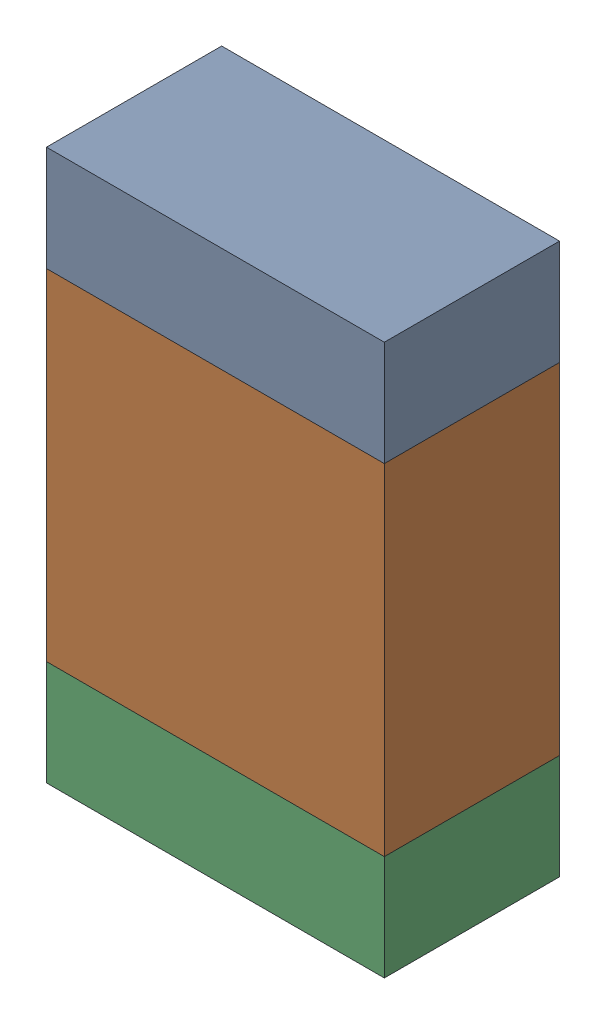
SolidWorks assembly R9-2, configuration Default. Lengths in mm.
Overall size (1.35 2.2 0.7).
6 component instances, 2 part files, 0 mates.
Components (placement in the parent):
- 959207304-2-1: 959207304-2 [Default] at (77.5971 95.5049 0) size (1.35 0.42 0.7)
  - Extruded-70-1: Extruded-70 [Default] at origin size (1.35 0.42 0.7)
- 959207440-2-1: 959207440-2 [Default] at (77.5971 94.6149 0) size (1.35 1.36 0.7)
  - Extruded-71-1: Extruded-71 [Default] at origin size (1.35 1.36 0.7)
- 959207304-2-2: 959207304-2 [Default] at (77.5971 93.7249 0) size (1.35 0.42 0.7)
  - Extruded-70-1: Extruded-70 [Default] at origin size (1.35 0.42 0.7)
